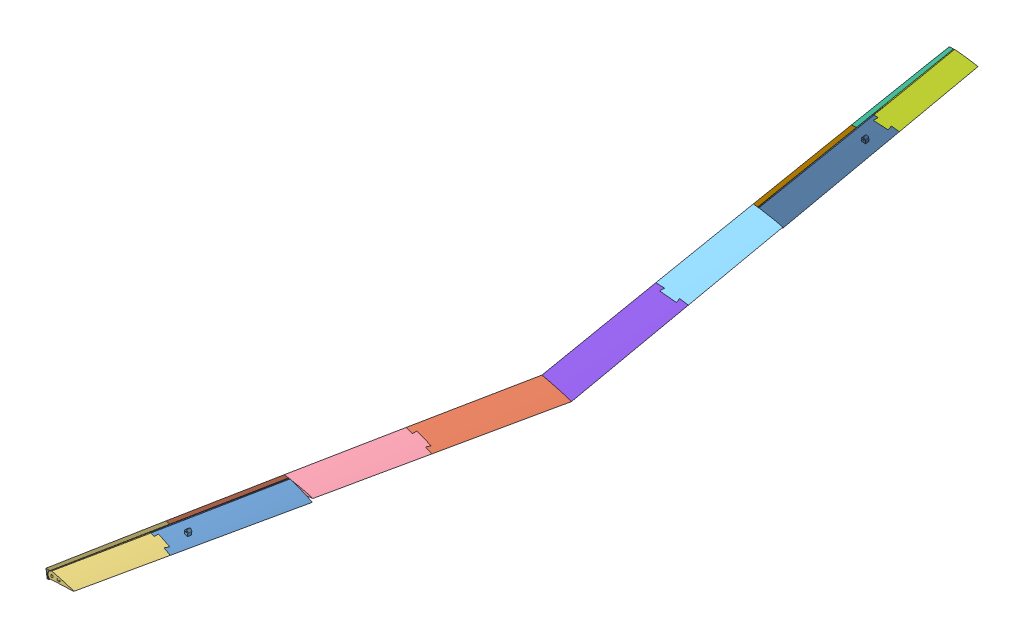
SolidWorks assembly Trailing edge Assem, configuration Default. Lengths in mm.
Overall size (103.71 67.69 1266.15).
12 component instances, 12 part files, 30 mates.
Components (placement in the parent):
- LI Aileron-1: LI Aileron [Default] at (0.8751 19.497 -1.6532) x (0.988183 -0.152812 0.011987) z (-0.013973 -0.011932 0.999831) size (54.93 27.11 181.99)
- LI Trailing Edge-1: LI Trailing Edge [Default] at origin size (58.91 28.44 177.81)
- LO Aileron-1: LO Aileron [Default] at (0.8751 19.497 -1.6532) x (0.988183 -0.152812 0.011987) z (-0.013973 -0.011932 0.999831) size (49.27 20.66 132.52)
- LO Trailing Edge-1: LO Trailing Edge [Default] at origin size (56.22 25.89 166.9)
- RO Trailing Edge-1: RO Trailing Edge [Default] at origin size (55.88 25.48 162.81)
- RO Fairing-1: RO Fairing [Default] at origin size (20.7 23.64 152.43)
- RO Aileron-1: RO Aileron [Default] at (0.0296 4.8634 0.4575) x (0.999106 -0.042094 -0.003843) z (0.003929 0.001975 0.99999) size (49.24 20.63 132.2)
- RI Trailing Edge-1: RI Trailing Edge [Default] at origin size (59.3 28.77 182.05)
- RI Fairing-1: RI Fairing [Default] at origin size (20.81 24.63 153.75)
- RI Aileron-1: RI Aileron [Default] at (0.0296 4.8634 0.4575) x (0.999106 -0.042094 -0.003843) z (0.003929 0.001975 0.99999) size (54.96 27.14 182.31)
- LI Fairing-1: LI Fairing [Default] at origin size (20.67 24.52 152.29)
- LO Fairing-1: LO Fairing [Default] at origin size (20.84 23.76 153.89)
Mates (geometry in assembly coordinates):
- Coincident1: coincident anti-aligned: plane of LI Fairing-1 through (73.9669 59.2707 478.2381) normal (-0.097286 0.081095 0.991947); plane of LO Fairing-1 through (73.9669 59.2707 478.2381) normal (0.097286 -0.081095 -0.991947)
- Coincident2: coincident: point of LI Fairing-1; point of LO Fairing-1
- Coincident3: coincident aligned: plane of LO Trailing Edge-1 through (118.9845 25.3866 9.594) normal (-0.974961 -0.208018 -0.078614); plane of LI Fairing-1 through (118.9845 25.3866 9.594) normal (-0.974961 -0.208018 -0.078614)
- Coincident4: coincident: point of LO Trailing Edge-1; point of LI Fairing-1
- Coincident5: coincident anti-aligned: plane of LI Trailing Edge-1 through (115.2281 23.6475 167.8454) normal (-0.100837 0.050901 0.9936); plane of LO Trailing Edge-1 through (115.2281 23.6475 167.8454) normal (0.100837 -0.050901 -0.9936)
- Coincident6: coincident anti-aligned: plane of LI Trailing Edge-1 through (115.7012 23.9418 174.2693) normal (0.996828 -0.034242 -0.071848); plane of LO Trailing Edge-1 through (115.7012 23.9418 174.2693) normal (-0.996828 0.034242 0.071848)
- Coincident7: coincident: point of LI Trailing Edge-1; point of LO Trailing Edge-1
- Coincident8: coincident anti-aligned: plane of LI Trailing Edge-1 through (60.8505 48.8206 0.1384) normal (0 0 -1); plane of RI Trailing Edge-1 through (60.8505 48.8206 0.1384) normal (0 0 1)
- Coincident9: coincident aligned: line of LI Trailing Edge-1 through (122.7151 11.4753 0.1384) axis (0.208664 -0.977987 0); line of RI Trailing Edge-1 through (122.7151 11.4753 0.1384) axis (0.208664 -0.977987 0)
- Coincident10: coincident: point of LI Trailing Edge-1; point of RI Trailing Edge-1
- Coincident11: coincident anti-aligned: plane of RO Trailing Edge-1 through (116.0818 20.8957 -171.9682) normal (0.09766 -0.082564 0.991789); plane of RI Trailing Edge-1 through (116.0818 20.8957 -171.9682) normal (-0.09766 0.082564 -0.991789)
- Coincident12: coincident: point of RO Trailing Edge-1; point of RI Trailing Edge-1
- Coincident13: coordinate: unknown of ?
- Coincident14: coincident anti-aligned: plane of RO Trailing Edge-1 through (0 23.0336 -329.1188) normal (0 0.069756 -0.997564); plane of RI Fairing-1 through (0 23.0336 -329.1188) normal (0 -0.069756 0.997564)
- Coincident15: coincident: point of RO Trailing Edge-1; point of RI Fairing-1
- Coincident16: coincident anti-aligned: plane of RO Fairing-1 through (74.4721 56.2291 -479.744) normal (0.097281 -0.081069 0.99195); plane of RI Fairing-1 through (74.4721 56.2291 -479.744) normal (-0.097281 0.081069 -0.99195)
- Coincident17: coincident: point of RO Fairing-1; point of RI Fairing-1
- Coincident18: coincident aligned: plane of RO Fairing-1 through (118.9845 25.3866 -9.3172) normal (-0.974961 -0.208018 0.078614); plane of RI Fairing-1 through (118.9845 25.3866 -9.3172) normal (-0.974961 -0.208018 0.078614)
- Coincident19: coincident aligned: plane of RO Trailing Edge-1 through (118.9845 25.3866 -9.3172) normal (-0.974961 -0.208018 0.078614); plane of RI Fairing-1 through (118.9845 25.3866 -9.3172) normal (-0.974961 -0.208018 0.078614)
- Coincident20: coincident aligned: plane of RO Trailing Edge-1 through (118.9845 25.3866 -9.3172) normal (-0.974961 -0.208018 0.078614); plane of RI Trailing Edge-1 through (118.9845 25.3866 -9.3172) normal (-0.974961 -0.208018 0.078614)
- Coincident21: coincident anti-aligned: plane of LI Aileron-1 through (104.3206 44.4216 502.7342) normal (-0.958246 0.074518 -0.276066); plane of LO Aileron-1 through (104.3206 44.4216 502.7342) normal (0.958246 -0.074518 0.276066)
- Coincident22: coincident anti-aligned: plane of LI Aileron-1 through (85.8768 46.1021 500.7702) normal (-0.098077 0.082623 0.991743); plane of LO Aileron-1 through (85.8768 46.1021 500.7702) normal (0.098077 -0.082623 -0.991743)
- Coincident23: coincident: point of LI Aileron-1; point of LO Aileron-1
- Concentric2: concentric anti-aligned: cylinder of LI Aileron-1 through (98.7186 32.7467 336.4102) axis (0.09759 -0.082579 -0.991795) radius 1.651; cylinder of LO Trailing Edge-1 through (99.9106 31.7381 324.2968) axis (-0.09759 0.082579 0.991795) radius 1.5875
- Coincident25: coincident: point of LI Aileron-1; plane of LO Trailing Edge-1 through (0 23.0336 329.3956) normal (0 0.069756 0.997564)
- Coincident26: coincident anti-aligned: plane of RO Aileron-1 through (85.855 46.5056 -500.8473) normal (0.098095 -0.082568 0.991746); plane of RI Aileron-1 through (85.855 46.5056 -500.8473) normal (-0.098095 0.082568 -0.991746)
- Coincident27: coincident anti-aligned: plane of RO Aileron-1 through (104.3871 46.9041 -502.6472) normal (0.962937 0.035412 -0.26739); plane of RI Aileron-1 through (104.3871 46.9041 -502.6472) normal (-0.962937 -0.035412 0.26739)
- Coincident28: coincident: point of RO Aileron-1; point of RI Aileron-1
- Concentric3: concentric anti-aligned: cylinder of RO Trailing Edge-1 through (99.9106 31.7381 -324.02) axis (-0.09759 0.082579 -0.991795) radius 1.5875; cylinder of RI Aileron-1 through (98.7128 32.7516 -336.1927) axis (0.09759 -0.082579 0.991795) radius 1.651
- Coincident29: coincident: plane of RO Trailing Edge-1 through (0 23.0336 -329.1188) normal (0 0.069756 -0.997564); point of RI Aileron-1
